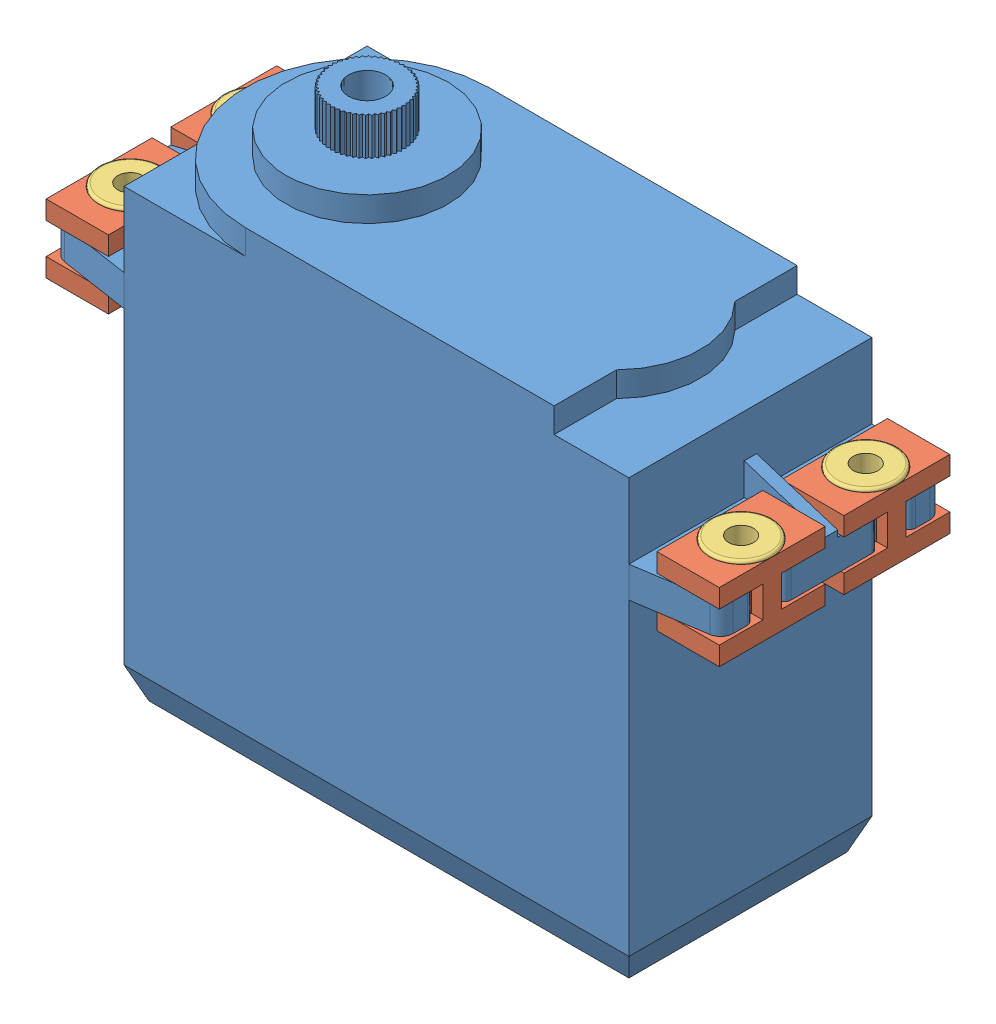
SolidWorks assembly MG996R Full Package, configuration Default. Lengths in mm.
Overall size (54 42.75 19.5).
9 component instances, 3 part files, 12 mates.
Components (placement in the parent):
- MG996R-1: MG996R [Default] at (12.0387 8.653 43.8185) size (53.5 42.75 19.5)
- MG996R Rubber Damper-1: MG996R Rubber Damper [Default] at (36.5387 34.403 48.8185) x (0 0 -1) z (1 0 0) size (8.5 5.5 5)
- MG996R Rubber Damper-2: MG996R Rubber Damper [Default] at (36.5387 34.403 38.8185) x (0 0 -1) z (1 0 0) size (8.5 5.5 5)
- MG996R Rubber Damper-3: MG996R Rubber Damper [Default] at (-12.4613 34.403 48.8185) x (0 0 1) z (-1 0 0) size (8.5 5.5 5)
- MG996R Rubber Damper-4: MG996R Rubber Damper [Default] at (-12.4613 34.403 38.8185) x (0 0 1) z (-1 0 0) size (8.5 5.5 5)
- Universal Damper Bush-1: Universal Damper Bush [Default] at (-12.4613 34.403 48.8185) size (5 5.75 5)
- Universal Damper Bush-2: Universal Damper Bush [Default] at (-12.4613 34.403 38.8185) size (5 5.75 5)
- Universal Damper Bush-3: Universal Damper Bush [Default] at (36.5387 34.403 48.8185) size (5 5.75 5)
- Universal Damper Bush-4: Universal Damper Bush [Default] at (36.5387 34.403 38.8185) size (5 5.75 5)
Mates (geometry in assembly coordinates):
- Coincident1: coincident aligned: circle of MG996R Rubber Damper-3; circle of Universal Damper Bush-1
- Coincident2: coincident aligned: circle of MG996R Rubber Damper-4; circle of Universal Damper Bush-2
- Coincident3: coincident aligned: circle of MG996R Rubber Damper-1; circle of Universal Damper Bush-3
- Coincident4: coincident aligned: circle of MG996R Rubber Damper-2; circle of Universal Damper Bush-4
- Coincident5: coincident anti-aligned: circle of MG996R-1; circle of MG996R Rubber Damper-1
- Coincident6: coincident anti-aligned: circle of MG996R-1; circle of MG996R Rubber Damper-2
- Coincident7: coincident anti-aligned: circle of MG996R-1; circle of MG996R Rubber Damper-3
- Coincident8: coincident anti-aligned: circle of MG996R-1; circle of MG996R Rubber Damper-4
- Parallel1: parallel aligned: plane of MG996R-1 through (-14.7113 35.903 47.5685) normal (-1 0 0); plane of MG996R Rubber Damper-4 through (-14.9613 35.903 34.5685) normal (-1 0 0)
- Parallel2: parallel aligned: plane of MG996R-1 through (-14.7113 35.903 47.5685) normal (-1 0 0); plane of MG996R Rubber Damper-3 through (-14.9613 35.903 44.5685) normal (-1 0 0)
- Parallel3: parallel aligned: plane of MG996R-1 through (38.7887 35.903 40.0685) normal (1 0 0); plane of MG996R Rubber Damper-1 through (39.0387 35.903 53.0685) normal (1 0 0)
- Parallel4: parallel aligned: plane of MG996R-1 through (38.7887 35.903 40.0685) normal (1 0 0); plane of MG996R Rubber Damper-2 through (39.0387 35.903 43.0685) normal (1 0 0)
